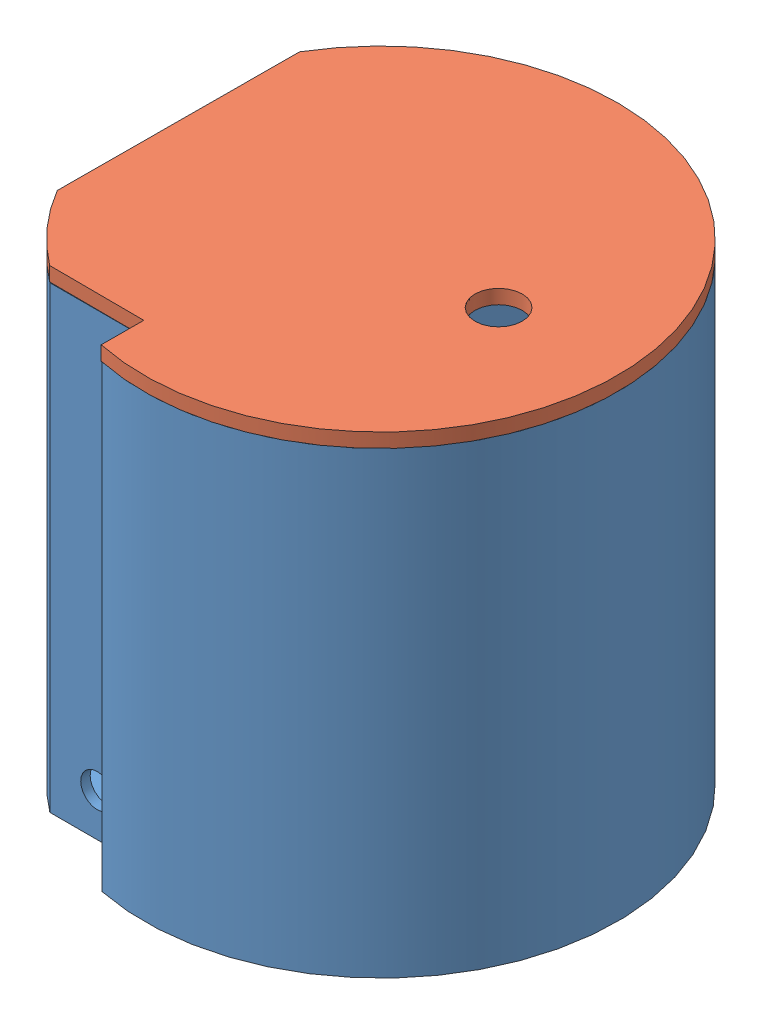
SolidWorks assembly Assem1, configuration Default. Lengths in mm.
Overall size (93.45 100 100.41).
2 component instances, 2 part files, 1 mates.
Components (placement in the parent):
- Bottom-1: Bottom [Default] at origin size (93 97 100)
- TOP-1: TOP [Default] at (0 97 0) x (0.99999 0 0.004466) z (-0.004466 0 0.99999) size (93 8 100)
Mates (geometry in assembly coordinates):
- Coincident1: coincident aligned: circle of Bottom-1; circle of TOP-1
